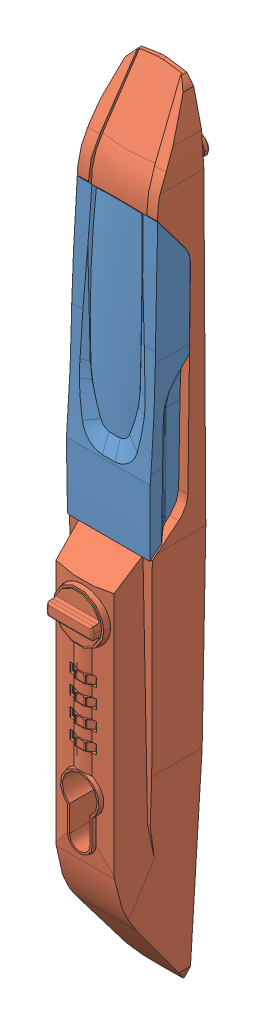
SolidWorks assembly 7030_601, configuration Default. Lengths in mm.
Overall size (41.07 386.21 52.36).
2 component instances, 2 part files, 6 mates.
Components (placement in the parent):
- 7030_601-lock-hindge-1: 7030_601-lock-hindge [Default] at (-20.3569 -217.5475 -46.6596) x (0 -1 0) z (-1 0 0) size (141.32 20.56 41.07)
- 7030_601-lock-base-1: 7030_601-lock-base [Default] at (-20.3569 -218.1 -46.65) x (0 -1 0) z (-1 0 0) size (386.21 52.36 40.86)
Mates (geometry in assembly coordinates):
- Abstand1: distance = 0.5 mm anti-aligned: plane of 7030_601-lock-base-1 through (-40.8569 -171.1201 -37.7875) normal (0 0.017452 0.999848); plane of 7030_601-lock-hindge-1 through (-40.8569 -73.5953 -38.9897) normal (0 -0.017452 -0.999848)
- Deckungsgleich2: coincident aligned: plane of 7030_601-lock-hindge-1 through (126.143 -217.5475 -46.6596) normal (-1 0 0); plane of 7030_601-lock-base-1 through (126.143 -271.1634 -519.5499) normal (-1 0 0)
- Abstand2: distance = 1.1278 mm: line of 7030_601-lock-base-1 through (-40.7479 -190.8066 -20.5193) axis (1 0 0); line of 7030_601-lock-hindge-1 through (-40.4446 -190.5112 -19.4309) axis (1 0 0)
- Deckungsgleich4: coincident aligned: plane of 7030_601-lock-base-1 through (-20.3569 -216.5132 0) normal (0 0 1); plane of assembly
- Deckungsgleich5: coincident aligned: plane of 7030_601-lock-base-1 through (-40.8569 0 -44.68) normal (0 1 0); plane of assembly
- Tangential1: tangent aligned: cylinder of 7030_601-lock-base-1 through (-5157.843 -145.7112 3.35) axis (0 0 -1) radius 5157.843; plane of assembly
